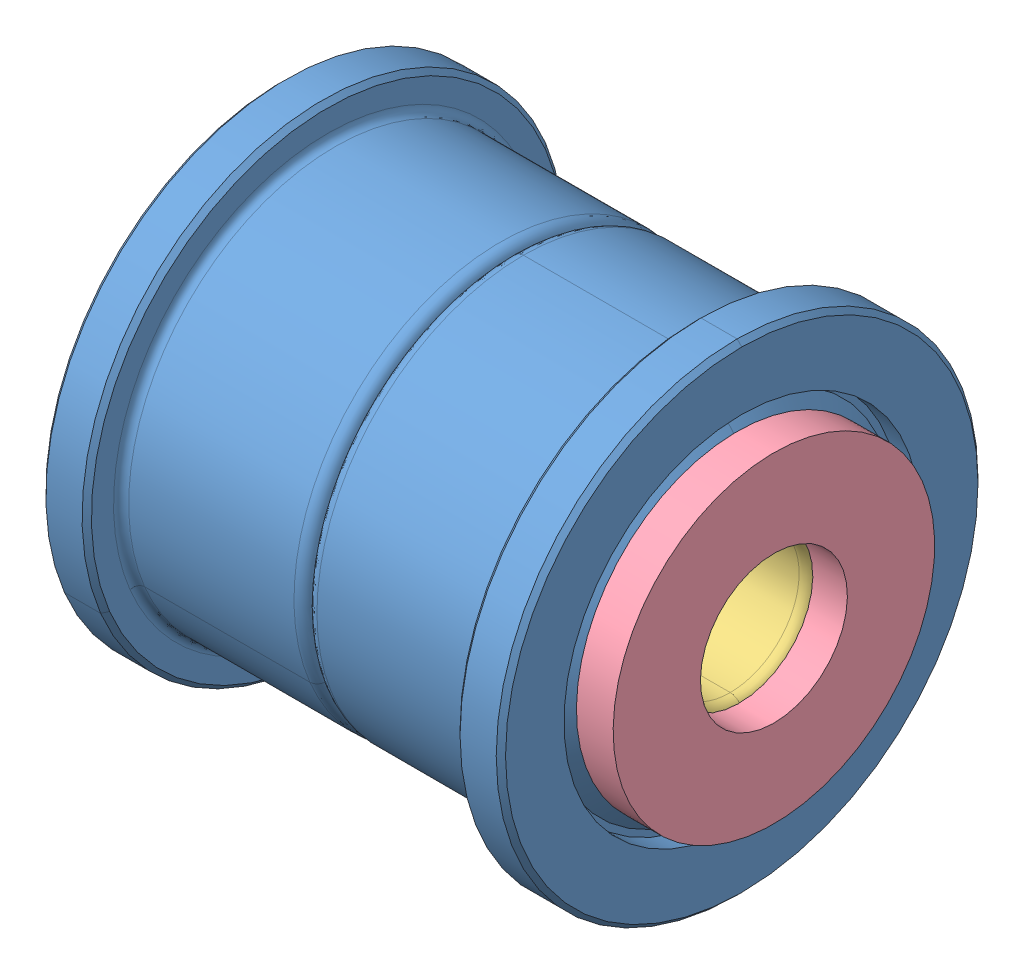
SolidWorks assembly Bearing assembly, configuration Default. Lengths in mm.
Overall size (22.35 13.72 13.72).
11 component instances, 6 part files, 7 mates.
Components (placement in the parent):
- F603HZZ-1: F603HZZ [Default] at origin size (5 10.49 10.49)
  - F603HZZ_SOLID_1-1: F603HZZ_SOLID_1 [Default] at origin size (5 10.49 10.49)
  - F603HZZ_SOLID_2-1: F603HZZ_SOLID_2 [Default] at origin size (3.13 7.92 8.2)
  - F603HZZ_SOLID_3-1: F603HZZ_SOLID_3 [Default] at origin size (5 4.24 4.24)
- F603HZZ-2: F603HZZ [Default] at (-5.0038 0 0) x (-1 0 0) z (0 -0.922978 -0.384852) size (5 10.49 10.49)
  - F603HZZ_SOLID_1-1: F603HZZ_SOLID_1 [Default] at origin size (5 10.49 10.49)
  - F603HZZ_SOLID_2-1: F603HZZ_SOLID_2 [Default] at origin size (3.13 7.92 8.2)
  - F603HZZ_SOLID_3-1: F603HZZ_SOLID_3 [Default] at origin size (5 4.24 4.24)
- plain washer 10673 type snl_iso1-1: plain washer 10673 type snl_iso1 [ISO 10673-3.2-S] at (2.4018 0 0) x (1 0 0) z (0 0.016518 0.999864) size (0.8 7 7)
- pan head cross recess screw_iso1-1: pan head cross recess screw_iso1 [ISO 7045 - M3 x 20 - Z --- 20N] at (-9.9057 0 0) x (1 0 0) z (0 -0.190019 0.98178) size (22.35 5.6 5.6)
- hex thin nut chamfered gradeab_iso1-1: hex thin nut chamfered gradeab_iso1 [Hexagon Thin Nut ISO - 4035 - M3 - N] at (9.0018 0 0) x (0 0.857652 -0.514231) z (1 0 0) size (5.5 6.35 1.8)
Mates (geometry in assembly coordinates):
- Concentric401055: concentric anti-aligned: cylinder of F603HZZ-1/F603HZZ_SOLID_3-1 through (-2.7521 0 0) axis (1 0 0) radius 1.4986; cylinder of F603HZZ-2/F603HZZ_SOLID_3-1 through (-2.2517 0 0) axis (-1 0 0) radius 1.4986
- Coincident7871306: coincident anti-aligned: plane of F603HZZ-1/F603HZZ_SOLID_1-1 through (-2.5019 0 0) normal (-1 0 0); plane of F603HZZ-2/F603HZZ_SOLID_1-1 through (-2.5019 0 0) normal (1 0 0)
- Coincident7871309: coincident anti-aligned: plane of F603HZZ-1/F603HZZ_SOLID_1-1 through (2.4018 0 0) normal (1 0 0); plane of plain washer 10673 type snl_iso-1 through (2.4018 0 0) normal (-1 0 0)
- Concentric401065: concentric aligned: cylinder of pan head cross recess screw_iso-1 through (-35.3057 0 0) axis (-1 0 0) radius 1.5; cylinder of plain washer 10673 type snl_iso-1 through (3.2018 0 0) axis (-1 0 0) radius 1.6
- Concentric401068: concentric aligned: cylinder of F603HZZ-2/F603HZZ_SOLID_3-1 through (-2.2517 0 0) axis (-1 0 0) radius 1.4986; cylinder of pan head cross recess screw_iso-1 through (-35.3057 0 0) axis (-1 0 0) radius 2.8
- Coincident7871314: coincident anti-aligned: plane of F603HZZ-2/F603HZZ_SOLID_1-1 through (-7.5057 0 0) normal (-1 0 0); plane of pan head cross recess screw_iso-1 through (-7.5057 1.4727 0.285) normal (1 0 0)
- Concentric401212: concentric aligned: cylinder of pan head cross recess screw_iso-1 through (-35.3057 0 0) axis (-1 0 0) radius 1.5; circle of hex thin nut chamfered gradeab_iso-1
